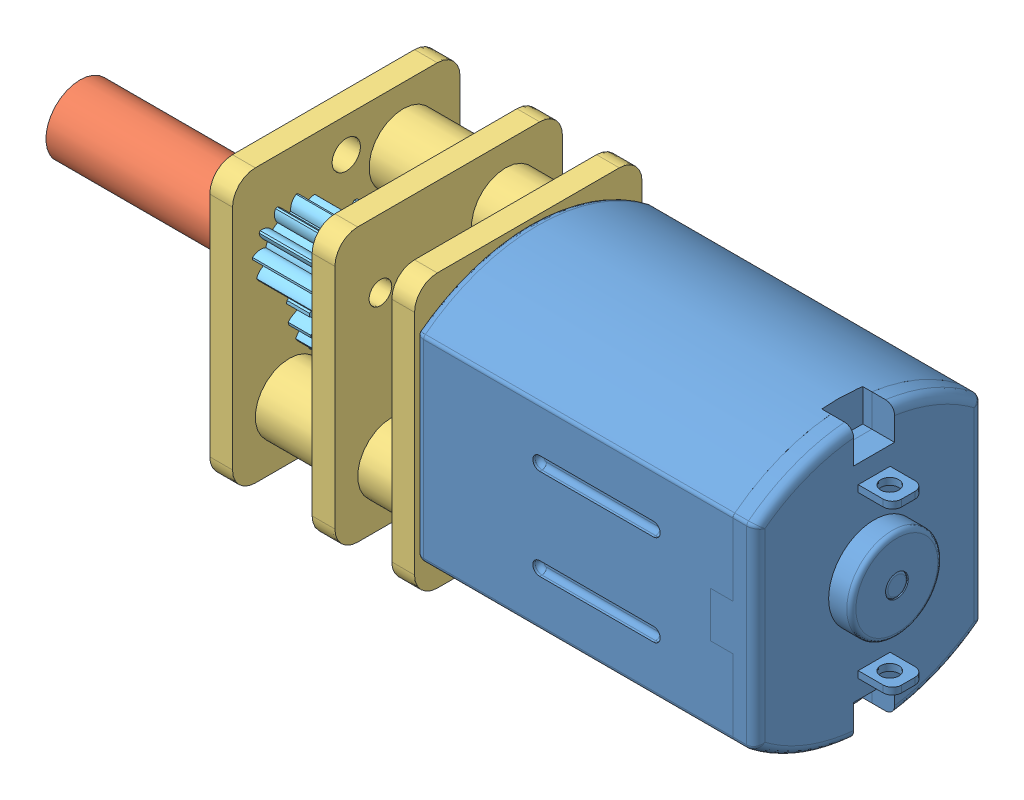
SolidWorks assembly n20 motor, configuration 轴长10mm. Lengths in mm.
Overall size (36.2 12.14 10.87).
11 component instances, 5 part files, 21 mates.
Components (placement in the parent):
- motor-1: motor [默认] at (-3.4114 0.0905 -5.0483)
- n20_shaft-1: n20_shaft [10mm] at (-13.1114 0.0905 -0.0483) x (0 -0.096252 -0.995357) z (0 0.995357 -0.096252) size (3 12 3)
- n20_gearbox-1: n20_gearbox [默认] at (-11.4114 0.0905 -0.0483) x (0 1 0) z (-1 0 0)
- cross recessed countersunk head screws gb1-1: cross recessed countersunk head screws gb1 [GB_CROSS_SCREWS_TYPE4 M1.6X3-2  H type-N] at (-12.4614 -3.4095 2.4517)
- cross recessed countersunk head screws gb1-2: cross recessed countersunk head screws gb1 [GB_CROSS_SCREWS_TYPE4 M1.6X3-2  H type-N] at (-12.4614 3.5905 -2.5483) x (1 0 0) z (0 0.116872 0.993147)
- spur gear_gb-1: spur gear_gb [GB - Spur gear 0.25M 10T 20PA 2FW ---S10A75H50L1.0N] at (-8.4114 -2.9095 -2.5483) x (1 0 0) z (0 -0.845955 0.533254)
- spur gear_gb-2: spur gear_gb [GB - Spur gear 0.25M 10T 20PA 2FW ---S10A75H50L1.0N] at (-4.4114 0.0905 -0.0483) x (-1 0 0) z (0 0.404067 -0.914729)
- spur gear_gb-4: spur gear_gb [GB - Spur gear 0.25M 16T 20PA 2FW ---S16A75H50L1.0N] at (-6.4114 -2.9095 -2.5483) x (1 0 0) z (0 -0.712706 0.701463)
- spur gear_gb-6: spur gear_gb [GB - Spur gear 0.25M 19T 20PA 2FW ---S19A75H50L1.0N] at (-9.9114 0.0905 -0.0483) x (1 0 0) z (0 0.321468 -0.94692)
- spur gear_gb-8: spur gear_gb [GB - Spur gear 0.25M 11T 20PA 3FW ---S11A75H50L1.0N] at (-10.9114 3.0905 2.9517) x (1 0 0) z (0 -0.604063 0.796937)
- spur gear_gb-10: spur gear_gb [GB - Spur gear 0.25M 19T 20PA 1FW ---S19A75H50L1.0N] at (-11.4114 0.0905 -0.0483) x (1 0 0) z (0 -0.330889 0.94367)
Mates (geometry in assembly coordinates):
- 同心1: concentric anti-aligned: cylinder of motor-1 through (-6.4114 0.0905 -0.0483) axis (1 0 0) radius 1; cylinder of n20_gearbox-1 through (-3.4114 0.0905 -0.0483) axis (-1 0 0) radius 0.5329
- 重合1: coincident anti-aligned: plane of motor-1 through (-3.4114 -5.9095 4.9517) normal (-1 0 0); plane of n20_gearbox-1 through (-3.4114 0.0905 -0.0483) normal (1 0 0)
- 重合2: coincident aligned: plane of motor-1 through (-3.4114 0.0905 4.9517) normal (0 0 1); plane of n20_gearbox-1 through (-3.4114 6.0905 4.9517) normal (0 0 1)
- 同心2: concentric aligned: cylinder of n20_shaft-1 through (-23.1114 0.0905 -0.0483) axis (1 0 0) radius 1.5; cylinder of n20_gearbox-1 through (-12.4114 0.0905 -0.0483) axis (1 0 0) radius 1.5
- 同心3: concentric anti-aligned: cylinder of n20_gearbox-1 through (-7.9114 3.5905 -2.5483) axis (-1 0 0) radius 0.9; cone of cross recessed countersunk head screws gb1-2 through (-11.4614 3.5905 -2.5483) axis (1 0 0)
- 重合4: coincident aligned: cone of n20_gearbox-1 through (-12.4114 3.5905 -2.5483) axis (1 0 0); cone of cross recessed countersunk head screws gb1-2 through (-11.4614 3.5905 -2.5483) axis (1 0 0)
- 同心8: concentric anti-aligned: cylinder of n20_gearbox-1 through (-7.9114 -3.4095 2.4517) axis (-1 0 0) radius 0.9; cylinder of cross recessed countersunk head screws gb1-1 through (-7.9456 -3.4095 2.4517) axis (1 0 0) radius 0.8
- 重合5: coincident aligned: cone of n20_gearbox-1 through (-12.4114 -3.4095 2.4517) axis (1 0 0); cone of cross recessed countersunk head screws gb1-1 through (-11.4614 -3.4095 2.4517) axis (1 0 0)
- 同心10: concentric aligned: cylinder of motor-1 through (-6.4114 0.0905 -0.0483) axis (1 0 0) radius 1; cylinder of spur gear_gb-2 through (-54.4115 0.0905 -0.0483) axis (1 0 0) radius 0.5
- 同心11: concentric aligned: cylinder of n20_gearbox-1 through (-3.4114 -2.9095 -2.5483) axis (-1 0 0) radius 0.5; cylinder of spur gear_gb-4 through (43.5886 -2.9095 -2.5483) axis (-1 0 0) radius 0.5
- 重合6: coincident anti-aligned: plane of n20_gearbox-1 through (-4.4114 0.0905 -0.0483) normal (-1 0 0); plane of spur gear_gb-4 through (-4.4114 -2.9095 -2.5483) normal (1 0 0)
- 同心12: concentric aligned: cylinder of n20_gearbox-1 through (-6.9114 0.0905 -0.0483) axis (-1 0 0) radius 0.5; cylinder of spur gear_gb-6 through (40.0886 0.0905 -0.0483) axis (-1 0 0) radius 0.5
- 重合7: coincident anti-aligned: plane of n20_gearbox-1 through (-7.9114 0.0905 -0.0483) normal (-1 0 0); plane of spur gear_gb-6 through (-7.9114 0.0905 -0.0483) normal (1 0 0)
- 同心13: concentric aligned: cylinder of spur gear_gb-1 through (41.5886 -2.9095 -2.5483) axis (-1 0 0) radius 0.5; cylinder of spur gear_gb-4 through (43.5886 -2.9095 -2.5483) axis (-1 0 0) radius 0.5
- 重合8: coincident anti-aligned: plane of spur gear_gb-1 through (-6.4114 -2.9095 -2.5483) normal (1 0 0); plane of spur gear_gb-4 through (-6.4114 -2.9095 -2.5483) normal (-1 0 0)
- 同心14: concentric aligned: cylinder of n20_gearbox-1 through (-6.9114 3.0905 2.9517) axis (-1 0 0) radius 0.5; cylinder of spur gear_gb-8 through (39.0886 3.0905 2.9517) axis (-1 0 0) radius 0.5
- 同心15: concentric aligned: cylinder of spur gear_gb-6 through (40.0886 0.0905 -0.0483) axis (-1 0 0) radius 0.5; cylinder of spur gear_gb-10 through (38.5886 0.0905 -0.0483) axis (-1 0 0) radius 0.5
- 重合9: coincident anti-aligned: plane of n20_gearbox-1 through (-7.9114 0.0905 -0.0483) normal (-1 0 0); plane of spur gear_gb-8 through (-7.9114 3.0905 2.9517) normal (1 0 0)
- 重合10: coincident anti-aligned: plane of n20_gearbox-1 through (-11.4114 0.0905 -0.0483) normal (1 0 0); plane of spur gear_gb-10 through (-11.4114 0.0905 -0.0483) normal (-1 0 0)
- 重合11: coincident anti-aligned: plane of n20_gearbox-1 through (-4.4114 0.0905 -0.0483) normal (-1 0 0); plane of spur gear_gb-2 through (-4.4114 0.0905 -0.0483) normal (1 0 0)
- Coincident2: coincident aligned: plane of n20_shaft-1 through (-13.1114 0.0905 -0.0483) normal (-1 0 0); plane of n20_gearbox-1 through (-13.1114 0.0905 -0.0483) normal (-1 0 0)
